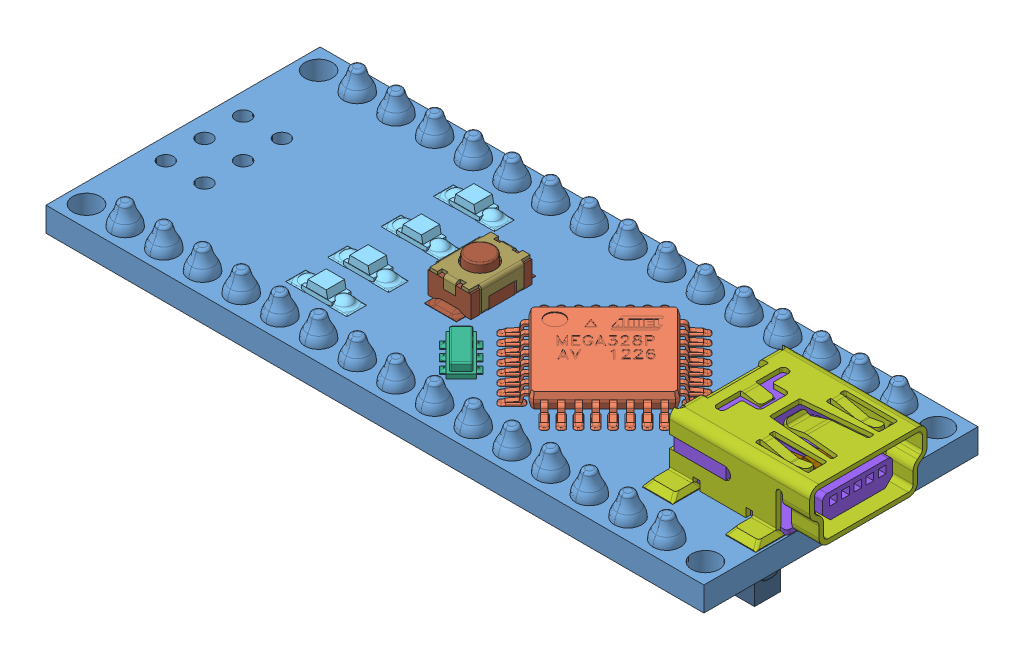
SolidWorks assembly User Library-arduino_nano, configuration Default. Lengths in mm.
Overall size (45 7.28 18).
28 component instances, 16 part files, 0 mates.
Components (placement in the parent):
- User Library-arduino_nano_nano-board-1: User Library-arduino_nano_nano-board [Default] at origin size (43.2 4.6 18)
- User Library-arduino_nano_atmega328-1: User Library-arduino_nano_atmega328 [Default] at (23.85 1.75 -7.62) x (-0.707107 0 0.707107) z (-0.707107 0 -0.707107) size (10 1.11 10)
- User Library-arduino_nano_ftdi FT232rl-1: User Library-arduino_nano_ftdi FT232rl [Default] at (29.05 0 -7.67) x (0 0 -1) z (-1 0 0) size (9.25 1.9 10.2)
- User Library-arduino_nano_smt_resistor222-1: User Library-arduino_nano_smt_resistor222 [Default] at (21.86 0 -5.8) x (0 0 -1) z (-1 0 0) size (1.7 0.6 3.8)
- User Library-arduino_nano_smt_resistor222-2: User Library-arduino_nano_smt_resistor222 [Default] at (21.86 0 -9) x (0 0 -1) z (-1 0 0) size (1.7 0.6 3.8)
- User Library-arduino_nano_smt_resistor222-3: User Library-arduino_nano_smt_resistor222 [Default] at (36.75 0 -7.6) x (0 0 -1) z (-1 0 0) size (1.7 0.6 3.8)
- User Library-arduino_nano_smt_resistor222-4: User Library-arduino_nano_smt_resistor222 [Default] at (36.75 0 -12) x (0 0 -1) z (-1 0 0) size (1.7 0.6 3.8)
- User Library-arduino_nano_smt_resistor222-5: User Library-arduino_nano_smt_resistor222 [Default] at (8.2 0 -2.6) x (0 0 -1) z (-1 0 0) size (1.7 0.6 3.8)
- User Library-arduino_nano_led-1: User Library-arduino_nano_led [Default] at (10.4 1.6 -2.8) size (4 0.9 1.55)
- User Library-arduino_nano_led-2: User Library-arduino_nano_led [Default] at (10.4 1.6 -5.55) size (4 0.9 1.55)
- User Library-arduino_nano_led-3: User Library-arduino_nano_led [Default] at (10.4 1.6 -12.5) size (4 0.9 1.55)
- User Library-arduino_nano_led-4: User Library-arduino_nano_led [Default] at (10.4 1.6 -9.05) size (4 0.9 1.55)
- User Library-arduino_nano_16mhz crystal - measured-1: User Library-arduino_nano_16mhz crystal - measured [Default] at (18.5113 1.6 -3.5541) x (0.707107 0 0.707107) z (-0.707107 0 0.707107) size (3.4 0.8 2)
- User Library-arduino_nano_MINIUSBSHELL-1: User Library-arduino_nano_MINIUSBSHELL [Default] at (38.98 1.65 -7.62) x (0 0 1) z (-1 0 0) size (10.9 3.85 9.41)
- User Library-arduino_nano_MINIUSBCORE-1: User Library-arduino_nano_MINIUSBCORE [Default] at (32.28 1.65 -7.62) x (0 0 -1) z (1 0 0) size (7.7 4.5 8.2)
- User Library-arduino_nano_MINI USB CONTACT-1: User Library-arduino_nano_MINI USB CONTACT [Default] at (33.28 1.65 -9.22) x (0 0 -1) z (1 0 0) size (0.53 2.55 9.41)
- User Library-arduino_nano_MINI USB CONTACT-2: User Library-arduino_nano_MINI USB CONTACT [Default] at (33.28 1.65 -8.42) x (0 0 -1) z (1 0 0) size (0.53 2.55 9.41)
- User Library-arduino_nano_MINI USB CONTACT-3: User Library-arduino_nano_MINI USB CONTACT [Default] at (33.28 1.65 -7.62) x (0 0 -1) z (1 0 0) size (0.53 2.55 9.41)
- User Library-arduino_nano_MINI USB CONTACT-4: User Library-arduino_nano_MINI USB CONTACT [Default] at (33.28 1.65 -6.82) x (0 0 -1) z (1 0 0) size (0.53 2.55 9.41)
- User Library-arduino_nano_MINI USB CONTACT-5: User Library-arduino_nano_MINI USB CONTACT [Default] at (33.28 1.65 -6.02) x (0 0 -1) z (1 0 0) size (0.53 2.55 9.41)
- User Library-arduino_nano_cap106C-1: User Library-arduino_nano_cap106C [Default] at (37.2 0 -3.3) x (0 0 1) z (1 0 0) size (1.7 1.81 4)
- User Library-arduino_nano_cap106C-2: User Library-arduino_nano_cap106C [Default] at (7.9 0 -5.6) x (0 0 -1) z (-1 0 0) size (1.7 1.81 4)
- User Library-arduino_nano_reset core-1: User Library-arduino_nano_reset core [Default] at (15.25 1.6 -8.05) x (0 0 -1) z (1 0 0) size (5.2 2.15 2.8)
- User Library-arduino_nano_reset shell-1: User Library-arduino_nano_reset shell [Default] at (15.25 3.25 -8.05) size (3 1.65 4)
- User Library-arduino_nano_nano - reg-1: User Library-arduino_nano_nano - reg [Default] at (6.1 0 -10.16) x (0 0 -1) z (-1 0 0) size (6.5 1.69 8.3)
- User Library-arduino_nano_NANO DIODE-1: User Library-arduino_nano_NANO DIODE [Default] at (11.43 0 -4.2) x (0 0 1) z (1 0 0) size (4.92 1.38 1.7)
- User Library-arduino_nano_189 RESISTOR PACK-1: User Library-arduino_nano_189 RESISTOR PACK [Default] at (15.75 0 -10.85) x (0 0 1) z (1 0 0) size (3.2 0.51 3)
- User Library-arduino_nano_102 RESISTOR PACK-1: User Library-arduino_nano_102 RESISTOR PACK [Default] at (15.75 0 -5.2) x (0 0 1) z (1 0 0) size (3.2 0.51 3)
